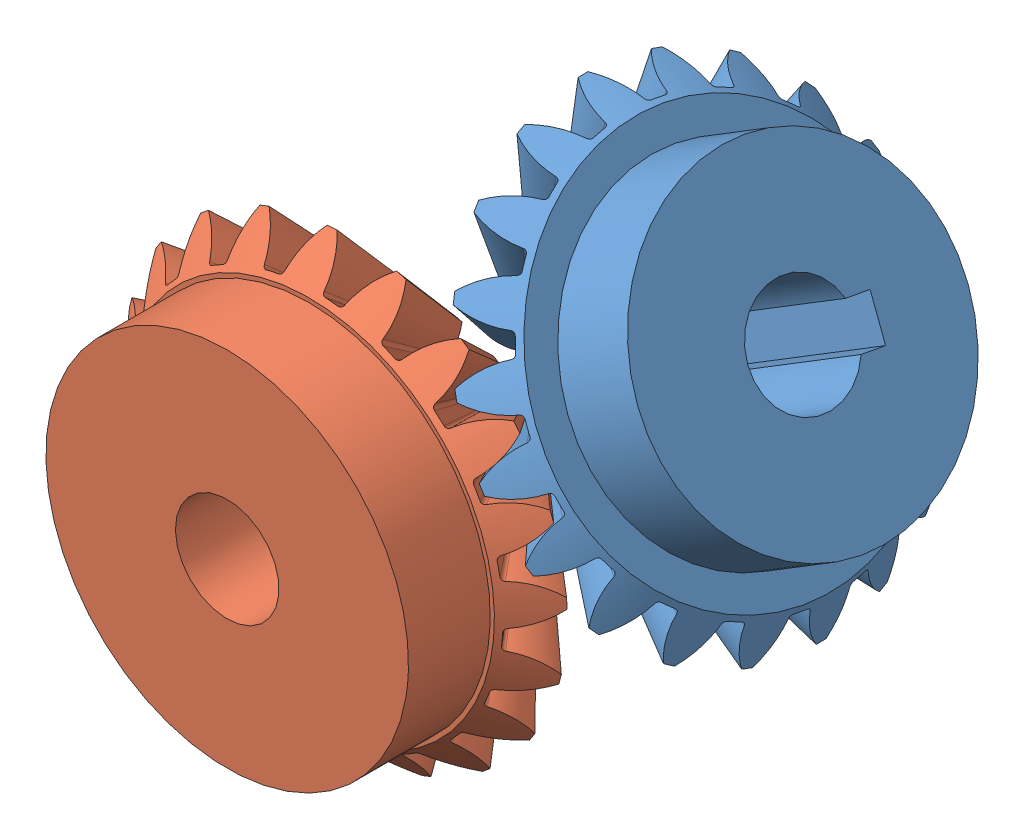
SolidWorks assembly Pinion Gear System, configuration Default. Lengths in mm.
Overall size (61.52 59.61 54.17).
2 component instances, 2 part files, 4 mates.
Components (placement in the parent):
- straight bevel gear_am-1: straight bevel gear_am [Metric - Straight bevel gear 2M 20GT 20PT 20PA 12FW ---20O30H30MD10S1] at (-262.163 -1559.3749 -30.0001) x (-0.852169 -0.523267 0) z (0.517885 -0.843404 0.143055) size (19.85 42.67 42.67)
- PinionGearAssem-1: PinionGearAssem [Metric - Straight bevel pinion 2M20PT 20GT 20PA 12FW ---20O35H30MD10N] at (-280.9968 -1570.9396 -7.8991) x (0 0 -1) z (0.995257 -0.097283 0) size (19.85 42.67 42.67)
Mates (geometry in assembly coordinates):
- Coincident2: coincident: point of straight bevel gear_am-1; point of PinionGearAssem-1
- Perpendicular1: perpendicular: line of straight bevel gear_am-1 through (-253.6413 -1554.1422 -30.0001) axis (-0.852169 -0.523267 0); line of straight bevel pinion_am-1 through (-280.9968 -1570.9396 2.1009) axis (0 0 -1)
- Coincident4: coincident aligned: plane of straight bevel pinion_am-1 through (-280.9968 -1570.9396 0) normal (0 0 1)
- GearMate1: gear = 25.4 : 25.4 mm: cone of straight bevel gear_am-1 through (-270.1535 -1564.2814 -30.0001) axis (0.852169 0.523267 0); cone of straight bevel pinion_am-1 through (-280.9968 -1570.9396 -17.2758) axis (0 0 1)
